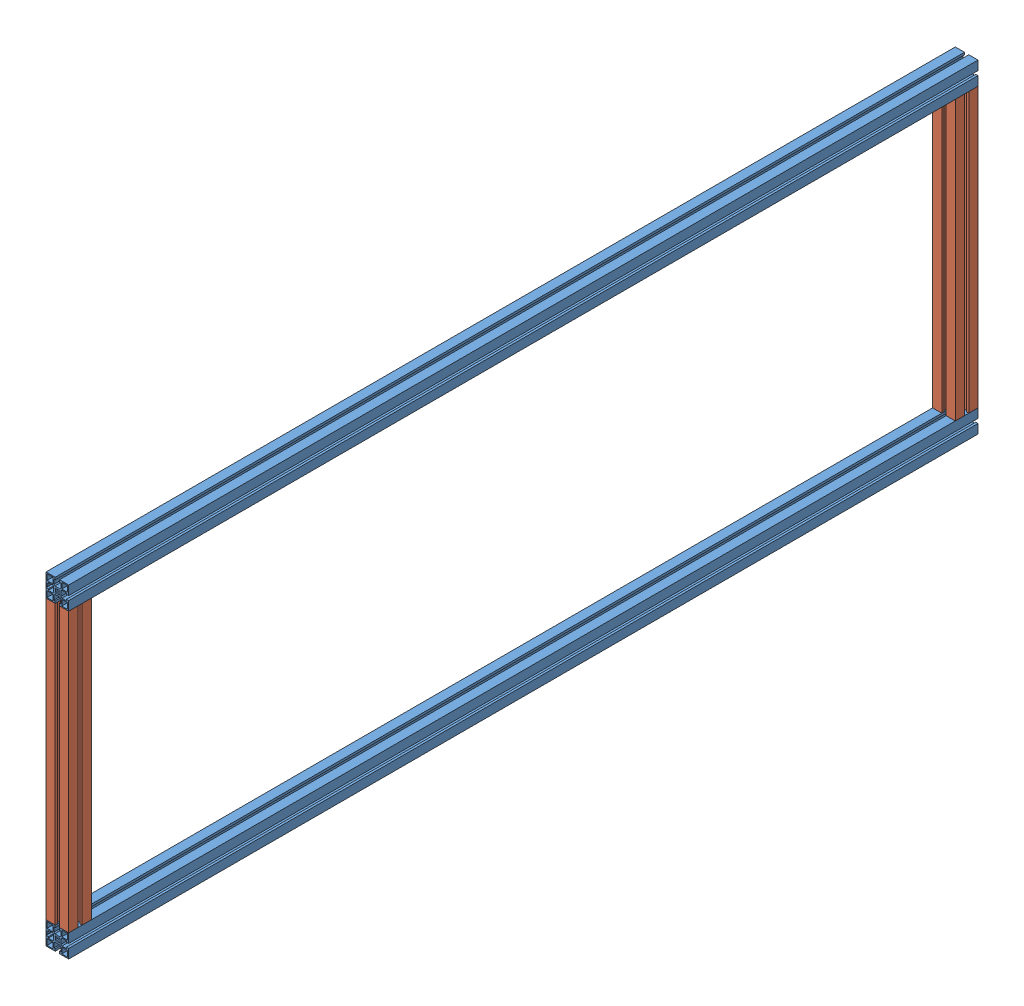
SolidWorks assembly door, configuration Default. Lengths in mm.
Overall size (45 642.45 1803.4).
4 component instances, 2 part files, 6 mates.
Components (placement in the parent):
- 20.1028 45X45 G_71_5in-1: 20.1028 45X45 G_71_5in [inner] at origin size (45 45 1803.4)
- 20.1028 45X45 G_18_125in-2: 20.1028 45X45 G_18_125in [Default] at (-0.0002 574.9493 22.4995) x (0 0 1) z (0 -1 0) size (45 45 552.45)
- 20.1028 45X45 G_18_125in-4: 20.1028 45X45 G_18_125in [Default] at (-0.0002 574.9493 1780.8995) x (0 0 1) z (0 -1 0) size (45 45 552.45)
- 20.1028 45X45 G_71_5in-2: 20.1028 45X45 G_71_5in [inner] at (0 597.4486 1803.4) x (1 0 0) z (0 0 -1) size (45 45 1803.4)
Mates (geometry in assembly coordinates):
- Coincident1: coincident: point of 20.1028 45X45 G_71_5in-1; point of 20.1028 45X45 G_18_125in-2
- Coincident2: coincident: point of 20.1028 45X45 G_71_5in-1; point of 20.1028 45X45 G_18_125in-2
- Coincident3: coincident: line of 20.1028 45X45 G_71_5in-1 through (-22.4995 22.4993 1803.4) axis (0 0 -1); point of 20.1028 45X45 G_18_125in-2
- Coincident5: coincident: line of 20.1028 45X45 G_71_5in-1 through (-22.4995 22.4993 1803.4) axis (0 0 -1); point of 20.1028 45X45 G_18_125in-4
- Coincident7: coincident: point of 20.1028 45X45 G_71_5in-1; point of 20.1028 45X45 G_18_125in-4
- Coincident8: coincident anti-aligned: line of 20.1028 45X45 G_71_5in-1 through (22.5005 22.4993 1803.4) axis (0 0 -1); line of 20.1028 45X45 G_18_125in-4 through (22.5005 22.4993 1758.4) axis (0 0 1)
